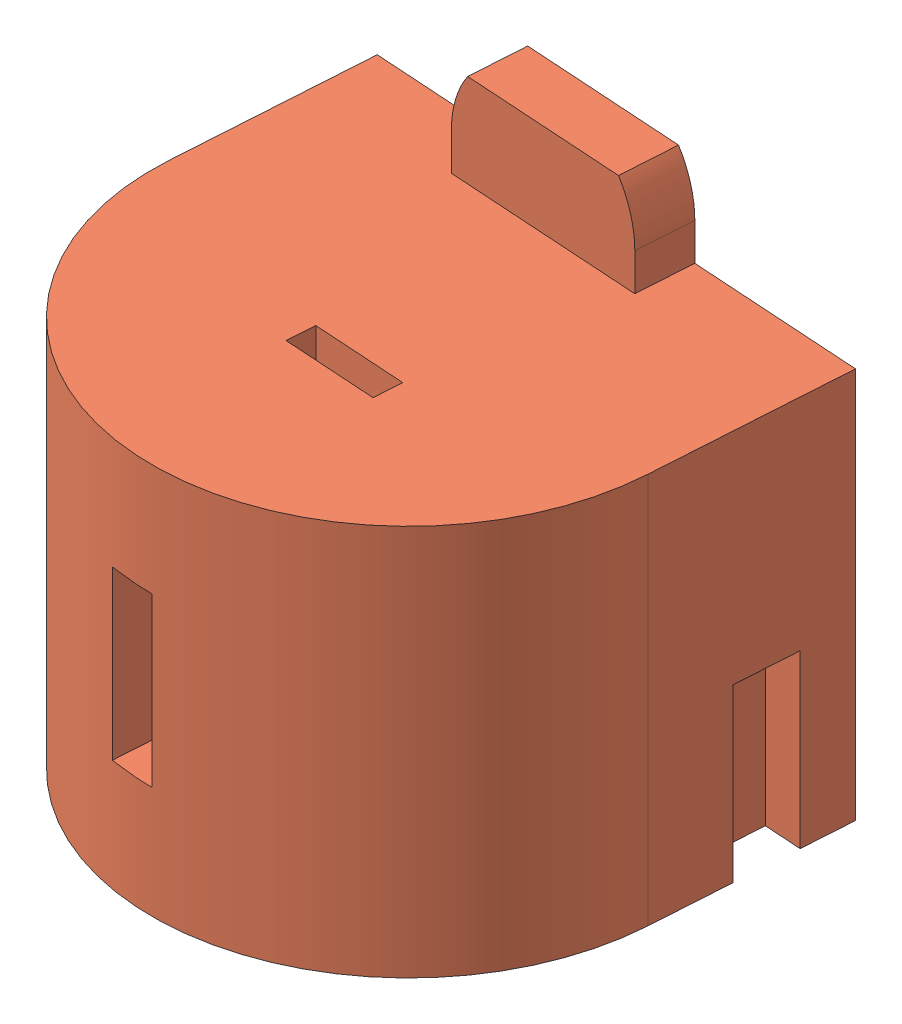
SolidWorks assembly 4xCR2032, configuration По умолчанию. Lengths in mm.
Overall size (29 26 25.97).
5 component instances, 2 part files, 8 mates.
Components (placement in the parent):
- CR2032 battery-1: CR2032 battery [Default] at (-29.7105 -3.9537 32.0638) size (20 3.2 20)
- CR2032 battery-2: CR2032 battery [Default] at (-29.7105 -0.7037 32.0638) size (20 3.2 20)
- CR2032 battery-3: CR2032 battery [Default] at (-29.7105 2.5463 32.0638) size (20 3.2 20)
- CR2032 battery-4: CR2032 battery [Default] at (-29.7105 5.7963 32.0638) size (20 3.2 20)
- BAT_12V-1: BAT_12V [По умолчанию] at (2.965 -0.9793 34.1666) x (0.997936 0 0.064222) z (-0.064222 0 0.997936) size (27.5 26 24.25)
Mates (geometry in assembly coordinates):
- Расстояние2: distance = 0.05 mm anti-aligned: plane of CR2032 battery-1 through (-29.7105 -0.7537 32.0638) normal (0 1 0); plane of CR2032 battery-2 through (-29.7105 -0.7037 32.0638) normal (0 -1 0)
- Концентричный1: concentric aligned: cylinder of CR2032 battery-1 through (-29.7105 -3.9537 32.0638) axis (0 -1 0) radius 10; cylinder of CR2032 battery-2 through (-29.7105 -0.7037 32.0638) axis (0 -1 0) radius 10
- Концентричный2: concentric aligned: cylinder of CR2032 battery-2 through (-29.7105 -0.7037 32.0638) axis (0 -1 0) radius 10; cylinder of CR2032 battery-3 through (-29.7105 2.5463 32.0638) axis (0 -1 0) radius 10
- Расстояние4: distance = 0.05 mm anti-aligned: plane of CR2032 battery-3 through (-29.7105 2.5463 32.0638) normal (0 -1 0); plane of CR2032 battery-2 through (-29.7105 2.4963 32.0638) normal (0 1 0)
- Расстояние5: distance = 0.05 mm anti-aligned: plane of CR2032 battery-4 through (-29.7105 5.7963 32.0638) normal (0 -1 0); plane of CR2032 battery-3 through (-29.7105 5.7463 32.0638) normal (0 1 0)
- Концентричный3: concentric aligned: cylinder of CR2032 battery-3 through (-29.7105 2.5463 32.0638) axis (0 -1 0) radius 10; cylinder of CR2032 battery-4 through (-29.7105 5.7963 32.0638) axis (0 -1 0) radius 10
- Расстояние6: distance = 1 mm anti-aligned: plane of CR2032 battery-4 through (-29.7105 8.9963 32.0638) normal (0 1 0); plane of BAT_12V-1 through (-29.7105 9.9963 32.0638) normal (0 -1 0)
- Концентричный4: concentric anti-aligned: cylinder of CR2032 battery-4 through (-29.7105 5.7963 32.0638) axis (0 -1 0) radius 10; cylinder of BAT_12V-1 through (-29.7105 12.9963 32.0638) axis (0 1 0) radius 10.75
